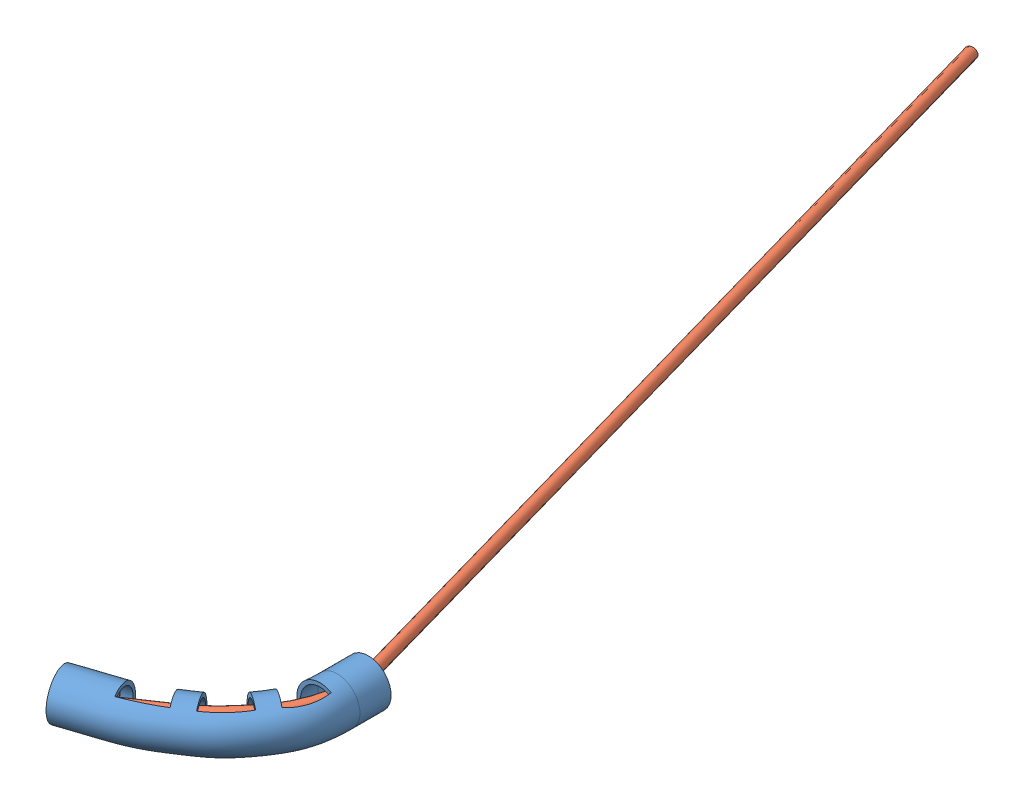
SolidWorks assembly cable + square joint_curve 3 assem, configuration Default. Lengths in mm.
Overall size (19.37 1.24 28.07).
2 component instances, 2 part files, 1 mates.
Components (placement in the parent):
- Arushri_Tube_SquareJoint_curve 3-1: Arushri_Tube_SquareJoint_curve 3 [Default] at (3.3174 3.4786 2.5513) size (4.78 1.24 15.36)
- cable_curve3-1: cable_curve3 [Default] at (0.023 3.4786 6.3562) x (-0.435084 0 -0.90039) z (0 1 0) size (26.06 8.92 0.5)
Mates (geometry in assembly coordinates):
- Coincident1: coincident anti-aligned: circle of Arushri_Tube_SquareJoint_curve 3-1; circle of cable_curve3-1
